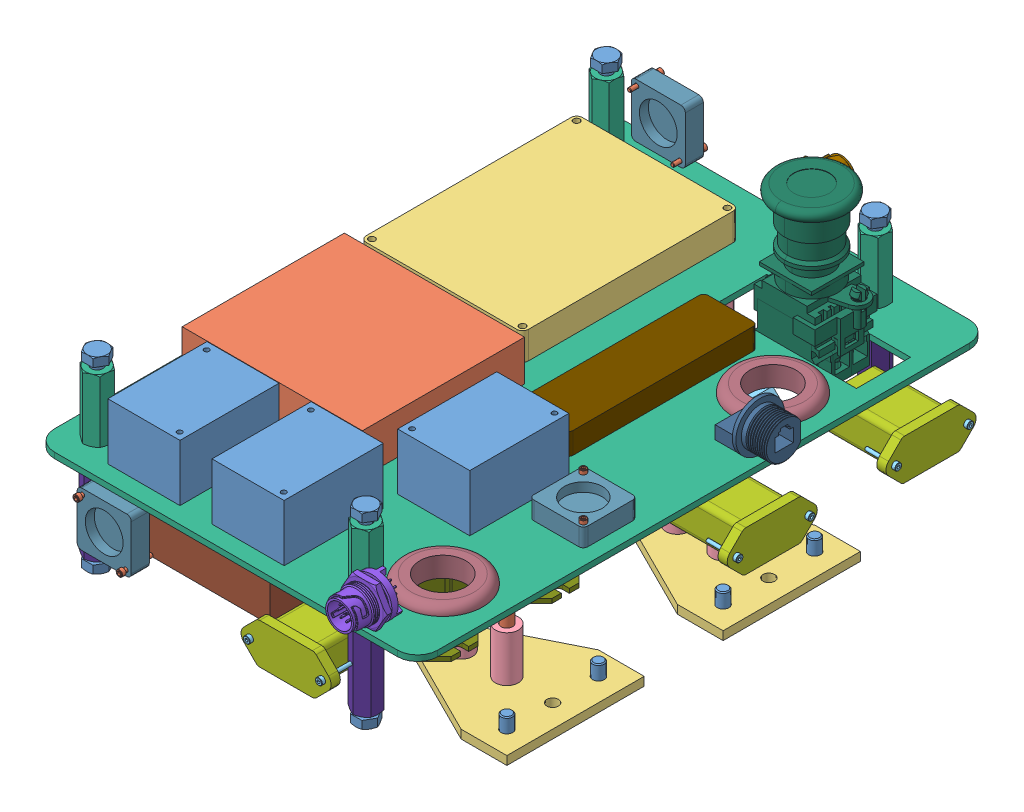
SolidWorks assembly ElectronicsCase2, configuration Default. Lengths in mm.
Overall size (226.41 163.38 353.07).
72 component instances, 27 part files, 172 mates.
Components (placement in the parent):
- Case-1: Case [Default] at (142.0655 -57.4073 111.1564) size (215.9 91.69 320.68) (hidden)
- EPOS$ EB Simple-1: EPOS$ EB Simple [Default] at (193.2592 221.0123 283.0081) x (1 0 0) z (0 0 -1) size (40 31.35 55)
- EPOS4 EB Micro-1: EPOS4 EB Micro [Default] at (252.5557 20.6679 36.3716) x (-1 0 0) z (0 0 1) size (100 22.5 90)
- LattePandaSimple-1: LattePandaSimple [Default] at (486.6352 212.549 -22.0114) x (0 0 -1) z (-1 0 0) size (120 15.18 90)
- EPOS$ EB Simple-2: EPOS$ EB Simple [Default] at (230.3992 -193.3265 -202.9705) size (40 31.35 55)
- EPOS$ EB Simple-3: EPOS$ EB Simple [Default] at (135.4792 221.0123 283.0081) x (1 0 0) z (0 0 -1) size (40 31.35 55)
- Cover^ElectronicsCase2-1: Cover^ElectronicsCase2 [Default] at (2.0429 34.2804 -33.3636) size (219.08 3.17 323.85) (hidden, virtual)
- Relay2-1: Relay2 [Default] at (225.8855 -55.8071 -151.3526) x (0 0 -1) z (0 1 0) size (45.49 58.42 35.56)
- Relay2-2: Relay2 [Default] at (167.4655 -55.8071 -151.3526) x (0 0 1) z (0 1 0) size (45.49 58.42 35.56)
- Terminal^ElectronicsCase2-1: Terminal^ElectronicsCase2 [Default] at (281.6155 -55.8071 -130.5286) x (1 0 0) z (0 0 -1) size (11.6 15.07 19.84) (virtual)
- Shelf^ElectronicsCase2-1: Shelf^ElectronicsCase2 [Default] at (0 -5.0071 0) size (212.7 3.17 317.47) (virtual)
- Part2^ElectronicsCase2-1: Part2^ElectronicsCase2 [Default] at origin (virtual)
- Power Plug ThroughHole^ElectronicsCase2-1: Power Plug ThroughHole^ElectronicsCase2 [Default] at (357.9655 -33.0571 -168.6436) x (0 0 1) z (-1 0 0) size (50 22.5 43.5) (virtual)
- Motor ThroughHole-1: Motor ThroughHole [Default] at (330.8405 16.2247 127.3562) x (0.866025 0.5 0) z (0 0 1) size (25.66 25.67 28.2)
- Electromagnet ThroughHole-1: Electromagnet ThroughHole [Default] at (256.4457 16.2247 -225.7184) x (-0.866025 0.5 0) z (0 0 -1) size (22.5 25.67 24.8)
- Power Plug ThroughHole^ElectronicsCase2-2: Power Plug ThroughHole^ElectronicsCase2 [Default] at (357.9655 -33.0571 -80.5436) x (0 0 1) z (-1 0 0) size (50 22.5 43.5) (virtual)
- Ethernet ThroughHole^ElectronicsCase2-1: Ethernet ThroughHole^ElectronicsCase2 [Default] at (356.3653 16.2247 -80.5436) x (0 0 1) z (-1 0 0) size (27 27 30.41) (virtual)
- Terminal^ElectronicsCase2-2: Terminal^ElectronicsCase2 [Default] at (281.6155 -55.8071 -150.3686) x (1 0 0) z (0 0 -1) size (11.6 15.07 19.84) (virtual)
- Power Supply^ElectronicsCase2-1: Power Supply^ElectronicsCase2 [Default] at (199.2155 -55.8071 1.8348) x (0 0 1) z (-1 0 0) size (154 40 88.9) (virtual)
- USB-C Adapter^ElectronicsCase2-1: USB-C Adapter^ElectronicsCase2 [Default] at (281.6155 -55.8071 -77.1111) x (0 0 -1) z (1 0 0) size (41.27 46.83 41.27) (virtual)
- Grommets3-1: Grommets3 [9600K217] at (325.8853 -2.6259 -118.1061) x (0.159498 0 0.987198) z (-0.987198 0 0.159498) size (44.45 11.11 44.45)
- Grommets3-2: Grommets3 [9600K217] at (325.8853 -2.6259 65.1062) x (-0.999275 0 0.038074) z (-0.038074 0 -0.999275) size (44.45 11.11 44.45)
- Power Plug ThroughHole^ElectronicsCase2-3: Power Plug ThroughHole^ElectronicsCase2 [Default] at (290.0905 -30.2823 111.1564) x (-1 0 0) z (0 0 -1) size (50 22.5 43.5) (virtual)
- Fan^ElectronicsCase2-1: Fan^ElectronicsCase2 [Default] at (182.4655 16.2247 -207.9184) size (30 30 10) (virtual)
- Fan^ElectronicsCase2-2: Fan^ElectronicsCase2 [Default] at (182.4655 -26.5323 99.5562) size (30 30 10) (virtual)
- Fan^ElectronicsCase2-3: Fan^ElectronicsCase2 [Default] at (333.3505 -1.8321 -5.4264) x (1 0 0) z (0 1 0) size (30 30 10) (virtual)
- Emergency Stop-1: Emergency Stop [Default] at (306.953 37.4554 -158.5061) x (0 0 1) z (0 1 0) size (40 46.39 86.7)
- Emergency Relay^ElectronicsCase2-1: Emergency Relay^ElectronicsCase2 [Default] at (277.6655 -55.8071 -17.1136) size (68 48.5 33) (virtual)
- Emergency Relay^ElectronicsCase2-2: Emergency Relay^ElectronicsCase2 [Default] at (277.6655 -55.8071 38.7464) size (68 48.5 33) (virtual)
- Standoff-1: Standoff [93505A200] at (310.3405 -24.0571 92.1064) x (0 1 0) z (-0.5 0 0.866025) size (64.39 14.66 12.7)
- Standoff-2: Standoff [93505A200] at (161.1155 -24.0571 92.1064) x (0 1 0) z (-0.5 0 0.866025) size (64.39 14.66 12.7)
- Standoff-3: Standoff [93505A200] at (161.1155 -24.0571 -190.4686) x (0 1 0) z (-1 0 0) size (64.39 14.66 12.7)
- Standoff-4: Standoff [93505A200] at (310.3405 -24.0571 -190.4686) x (0 1 0) z (-0.837138 0 0.546991) size (64.39 14.66 12.7)
- USB Hub^ElectronicsCase2-1: USB Hub^ElectronicsCase2 [Default] at (285.3217 -1.8321 -82.732) size (29.97 11.94 104.9) (virtual)
- hex bolt_ai-5: hex bolt_ai [HBOLT 0.2500-20x0.5x0.5-N] at (310.3405 -62.1825 92.1064) x (0 1 0) z (0 0 1) size (17.48 12.85 11.13)
- hex bolt_ai-6: hex bolt_ai [HBOLT 0.2500-20x0.5x0.5-N] at (161.1155 -62.1825 92.1064) x (0 1 0) z (0 0 1) size (17.48 12.85 11.13)
- hex bolt_ai-7: hex bolt_ai [HBOLT 0.2500-20x0.5x0.5-N] at (161.1155 -62.1825 -190.4686) x (0 1 0) z (0 0 1) size (17.48 12.85 11.13)
- hex bolt_ai-8: hex bolt_ai [HBOLT 0.2500-20x0.5x0.5-N] at (310.3405 -62.1825 -190.4686) x (0 1 0) z (0 0 1) size (17.48 12.85 11.13)
- socket head cap screw_ai-1: socket head cap screw_ai [HX-SHCS 0.086-56x0.625x0.625-N] at (170.4655 -14.5323 113.3408) x (0 0 -1) z (1 0 0) size (18.06 3.56 3.56)
- socket head cap screw_ai-2: socket head cap screw_ai [HX-SHCS 0.086-56x0.625x0.625-N] at (194.4655 -38.5323 113.3408) x (0 0 -1) z (1 0 0) size (18.06 3.56 3.56)
- socket head cap screw_ai-3: socket head cap screw_ai [HX-SHCS 0.086-56x0.625x0.625-N] at (170.4655 28.2247 -211.703) x (0 0 1) z (-1 0 0) size (18.06 3.56 3.56)
- socket head cap screw_ai-4: socket head cap screw_ai [HX-SHCS 0.086-56x0.625x0.625-N] at (194.4655 4.2247 -211.703) x (0 0 1) z (-1 0 0) size (18.06 3.56 3.56)
- socket head cap screw_ai-5: socket head cap screw_ai [HX-SHCS 0.086-56x0.625x0.625-N] at (321.3505 10.3523 -17.4264) x (0 -1 0) z (0 0 1) size (18.06 3.56 3.56)
- socket head cap screw_ai-7: socket head cap screw_ai [HX-SHCS 0.086-56x0.625x0.625-N] at (345.3505 10.3523 6.5736) x (0 -1 0) z (0 0 1) size (18.06 3.56 3.56)
- T-Framing-1: T-Framing [47065T278] at (345.2655 -85.1886 -71.0786) x (0 0 -1) z (0 1 0) size (76.2 76.2 4.76)
- T-Framing-2: T-Framing [47065T278] at (345.2655 -85.1886 48.9164) x (0 0 -1) z (0 1 0) size (76.2 76.2 4.76)
- hex bolt_ai-9: hex bolt_ai [HBOLT 0.2500-28x0.5x0.5-N] at (332.5655 -92.345 -134.5786) x (0 1 0) z (0 0 1) size (17.48 12.85 11.13)
- hex bolt_ai-10: hex bolt_ai [HBOLT 0.2500-28x0.5x0.5-N] at (332.5655 -92.345 -83.7786) x (0 1 0) z (0 0 1) size (17.48 12.85 11.13)
- hex bolt_ai-11: hex bolt_ai [HBOLT 0.2500-28x0.5x0.5-N] at (332.5655 -92.345 -14.5836) x (0 1 0) z (0 0 1) size (17.48 12.85 11.13)
- hex bolt_ai-12: hex bolt_ai [HBOLT 0.2500-28x0.5x0.5-N] at (332.5655 -92.345 36.2164) x (0 1 0) z (0 0 1) size (17.48 12.85 11.13)
- socket head cap screw_ai-8: socket head cap screw_ai [HX-SHCS 0.25-20x1.75x1.25-N] at (307.1655 -93.9198 -109.1786) x (0 1 0) z (0 0 1) size (50.8 9.53 9.53)
- socket head cap screw_ai-9: socket head cap screw_ai [HX-SHCS 0.25-20x1.75x1.25-N] at (281.7655 -93.9198 -109.1786) x (0 1 0) z (0 0 1) size (50.8 9.53 9.53)
- socket head cap screw_ai-10: socket head cap screw_ai [HX-SHCS 0.25-20x1.75x1.25-N] at (307.1655 -93.9198 10.8164) x (0 1 0) z (0 0 1) size (50.8 9.53 9.53)
- socket head cap screw_ai-11: socket head cap screw_ai [HX-SHCS 0.25-20x1.75x1.25-N] at (281.7655 -93.9198 10.8164) x (0 1 0) z (0 0 1) size (50.8 9.53 9.53)
- Spacers-1: Spacers [92510A769] at (307.1655 -70.1073 -109.1786) x (1 0 0) z (0 -1 0) size (12.7 12.7 25.4)
- Spacers-2: Spacers [92510A769] at (281.7655 -70.1073 -109.1786) x (1 0 0) z (0 -1 0) size (12.7 12.7 25.4)
- Spacers-3: Spacers [92510A769] at (281.7655 -70.1073 10.8164) x (1 0 0) z (0 -1 0) size (12.7 12.7 25.4)
- Spacers-4: Spacers [92510A769] at (307.1655 -70.1073 10.8164) x (1 0 0) z (0 -1 0) size (12.7 12.7 25.4)
- socket head cap screw_am-1: socket head cap screw_am [B18.3.1M - 2 x 0.4 x 16 Hex SHCS -- 16NHX] at (365.0655 -33.0571 -60.5436) x (-1 0 0) z (0 0.924225 0.381849) size (18 3.8 3.8)
- socket head cap screw_am-2: socket head cap screw_am [B18.3.1M - 2 x 0.4 x 16 Hex SHCS -- 16NHX] at (365.0655 -33.0571 -100.5436) x (-1 0 0) z (0 0.924225 0.381849) size (18 3.8 3.8)
- socket head cap screw_am-3: socket head cap screw_am [B18.3.1M - 2 x 0.4 x 16 Hex SHCS -- 16NHX] at (365.0655 -33.0571 -148.6436) x (-1 0 0) z (0 0.924225 0.381849) size (18 3.8 3.8)
- socket head cap screw_am-4: socket head cap screw_am [B18.3.1M - 2 x 0.4 x 16 Hex SHCS -- 16NHX] at (365.0655 -33.0571 -188.6436) x (-1 0 0) z (0 0.924225 0.381849) size (18 3.8 3.8)
- socket head cap screw_am-5: socket head cap screw_am [B18.3.1M - 2 x 0.4 x 16 Hex SHCS -- 16NHX] at (270.0905 -30.2823 118.2564) x (0 0 -1) z (1 0 0) size (18 3.8 3.8)
- socket head cap screw_am-6: socket head cap screw_am [B18.3.1M - 2 x 0.4 x 16 Hex SHCS -- 16NHX] at (310.0905 -30.2823 118.2564) x (0 0 -1) z (1 0 0) size (18 3.8 3.8)
- Standoff Top-1: Standoff Top [91780A666] at (310.3405 16.8191 92.1064) x (-0.401704 0 -0.915769) z (0 1 0) size (12.7 14.66 35.92)
- Standoff Top-2: Standoff Top [91780A666] at (310.3405 16.8191 -190.4686) x (-0.401704 0 -0.915769) z (0 1 0) size (12.7 14.66 35.92)
- Standoff Top-3: Standoff Top [91780A666] at (161.1155 16.8191 92.1064) x (-0.401704 0 -0.915769) z (0 1 0) size (12.7 14.66 35.92)
- Standoff Top-4: Standoff Top [91780A666] at (161.1155 16.8191 -190.4686) x (-0.401704 0 -0.915769) z (0 1 0) size (12.7 14.66 35.92)
- hex bolt_ai-13: hex bolt_ai [HBOLT 0.2500-20x0.5x0.5-N] at (310.3405 42.2306 -190.4686) x (0 -1 0) z (0 0 1) size (17.48 12.85 11.13)
- hex bolt_ai-14: hex bolt_ai [HBOLT 0.2500-20x0.5x0.5-N] at (161.1155 42.2306 -190.4686) x (0 -1 0) z (0 0 1) size (17.48 12.85 11.13)
- hex bolt_ai-15: hex bolt_ai [HBOLT 0.2500-20x0.5x0.5-N] at (161.1155 42.2306 92.1064) x (0 -1 0) z (0 0 1) size (17.48 12.85 11.13)
- hex bolt_ai-16: hex bolt_ai [HBOLT 0.2500-20x0.5x0.5-N] at (310.3405 42.2306 92.1064) x (0 -1 0) z (0 0 1) size (17.48 12.85 11.13)
Mates (geometry in assembly coordinates):
- Coincident3: coincident aligned: plane of EPOS$ EB Simple-2 through (299.0857 29.5179 21.8686) normal (0 1 0); plane of EPOS$ EB Simple-3 through (135.4792 29.5179 283.0081) normal (0 1 0)
- Coincident4: coincident aligned: plane of EPOS$ EB Simple-1 through (193.2592 29.5179 283.0081) normal (0 1 0); plane of EPOS$ EB Simple-3 through (135.4792 29.5179 283.0081) normal (0 1 0)
- Concentric1: concentric anti-aligned: cylinder of Case-1 through (345.2655 34.2816 -196.8186) axis (0 1 0) radius 12.7; cylinder of Cover^ElectronicsCase2-1 through (345.2655 35.8679 -196.8186) axis (0 -1 0) radius 14.2875
- Concentric2: concentric aligned: cylinder of Case-1 through (154.7655 34.2816 -196.8186) axis (0 -1 0) radius 12.7; cylinder of Cover^ElectronicsCase2-1 through (154.7655 35.8679 -196.8186) axis (0 -1 0) radius 14.2875
- Coincident37: coincident anti-aligned: plane of Case-1 through (142.0655 -55.8071 111.1564) normal (0 1 0); plane of Relay2-1 through (167.4655 -55.8071 -196.8186) normal (0 -1 0)
- Coincident38: coincident anti-aligned: plane of Case-1 through (142.0655 -55.8071 111.1564) normal (0 1 0); plane of Relay2-2 through (225.8855 -55.8071 -105.8866) normal (0 -1 0)
- Coincident67: coincident anti-aligned: plane of EPOS4 EB Micro-1 through (252.5557 -1.8321 36.3716) normal (0 -1 0); plane of Shelf^ElectronicsCase2-1 through (345.2655 -1.8321 98.4564) normal (0 1 0)
- Coincident68: coincident aligned: plane of EPOS4 EB Micro-1 through (252.5557 -1.8321 36.3716) normal (0 -1 0); plane of EPOS$ EB Simple-2 through (230.3992 -1.8321 -202.9705) normal (0 -1 0)
- Coincident69: coincident anti-aligned: plane of LattePandaSimple-1 through (233.9714 -1.8321 -102.8559) normal (0 -1 0); plane of Shelf^ElectronicsCase2-1 through (345.2655 -1.8321 98.4564) normal (0 1 0)
- Coincident72: coincident anti-aligned: plane of Case-1 through (356.3653 34.2816 111.1564) normal (-1 0 0); plane of Ethernet ThroughHole^ElectronicsCase2-1 through (356.3653 16.2247 -80.5436) normal (1 0 0)
- Coincident73: coincident aligned: plane of Power Plug ThroughHole^ElectronicsCase2-1 through (357.9655 -33.0571 -148.6436) normal (-1 0 0); plane of Power Plug ThroughHole^ElectronicsCase2-2 through (357.9655 -33.0571 -60.5436) normal (-1 0 0)
- Coincident74: coincident anti-aligned: plane of Case-1 through (357.9655 34.2816 111.1564) normal (1 0 0); plane of Power Plug ThroughHole^ElectronicsCase2-2 through (357.9655 -33.0571 -60.5436) normal (-1 0 0)
- Coincident75: coincident aligned: plane of Power Plug ThroughHole^ElectronicsCase2-1 through (363.0655 -21.8071 -154.0651) normal (0 1 0); plane of Power Plug ThroughHole^ElectronicsCase2-2 through (363.0655 -21.8071 -65.9651) normal (0 1 0)
- Perpendicular1: perpendicular: plane of Power Plug ThroughHole^ElectronicsCase2-2 through (363.0655 -21.8071 -65.9651) normal (0 1 0); plane of Ethernet ThroughHole^ElectronicsCase2-1 through (369.6653 10.9864 -89.6436) normal (0 0 -1)
- Parallel2: parallel aligned: plane of Case-1 through (142.0655 34.2816 111.1564) normal (0 1 0); plane of Power Plug ThroughHole^ElectronicsCase2-2 through (363.0655 -21.8071 -65.9651) normal (0 1 0)
- Coincident76: coincident anti-aligned: plane of Case-1 through (142.0655 -55.8071 111.1564) normal (0 1 0); plane of Terminal^ElectronicsCase2-1 through (281.6155 -55.8071 -130.5286) normal (0 -1 0)
- Coincident78: coincident aligned: plane of Terminal^ElectronicsCase2-1 through (281.6155 -40.7371 -130.5286) normal (0 1 0); plane of Terminal^ElectronicsCase2-2 through (281.6155 -40.7371 -150.3686) normal (0 1 0)
- Concentric10: concentric anti-aligned: cylinder of Case-1 through (154.7655 34.2816 98.4564) axis (0 1 0) radius 12.7; cylinder of Shelf^ElectronicsCase2-1 through (154.7655 -1.8321 98.4564) axis (0 -1 0) radius 11.0998
- Concentric11: concentric aligned: cylinder of Case-1 through (345.2655 34.2816 98.4564) axis (0 -1 0) radius 11.0998; cylinder of Shelf^ElectronicsCase2-1 through (345.2655 -1.8321 98.4564) axis (0 -1 0) radius 11.0998
- Distance4: distance = 12.7 mm anti-aligned: plane of Power Plug ThroughHole^ElectronicsCase2-1 through (319.5655 -43.1071 -157.7436) normal (0 -1 0); plane of Case-1 through (142.0655 -55.8071 111.1564) normal (0 1 0)
- Coincident83: coincident anti-aligned: plane of Case-1 through (142.0655 -55.8071 111.1564) normal (0 1 0); plane of Power Supply^ElectronicsCase2-1 through (199.2155 -55.8071 1.8348) normal (0 -1 0)
- Parallel3: parallel anti-aligned: plane of Case-1 through (356.3653 34.2816 111.1564) normal (-1 0 0); plane of Power Supply^ElectronicsCase2-1 through (243.6655 -15.8071 78.8348) normal (1 0 0)
- Distance6: distance = 6.35 mm anti-aligned: plane of EPOS$ EB Simple-1 through (193.2592 29.5179 283.0081) normal (0 1 0); plane of Cover^ElectronicsCase2-1 through (154.7655 35.8679 -196.8186) normal (0 -1 0)
- Coincident94: coincident anti-aligned: plane of Case-1 through (142.0655 -55.8071 111.1564) normal (0 1 0); plane of USB-C Adapter^ElectronicsCase2-1 through (281.6155 -55.8071 -77.1111) normal (0 -1 0)
- Distance11: distance = 8.89 mm anti-aligned: plane of LattePandaSimple-1 through (185.3257 -151.8321 -62.5184) normal (0 0 1); plane of EPOS4 EB Micro-1 through (252.5557 -1.8321 -53.6284) normal (0 0 -1)
- Coincident103: coincident: line of Case-1 through (154.7655 -57.4073 98.4564) axis (0 0 -1); plane of Power Supply^ElectronicsCase2-1 through (154.7655 -15.8071 78.8348) normal (-1 0 0)
- Distance14: distance = 8.89 mm anti-aligned: plane of LattePandaSimple-1 through (152.5557 -151.8321 -104.2384) normal (-1 0 0); plane of Case-1 through (143.6657 34.2816 111.1564) normal (1 0 0)
- Distance17: distance = 17.78 mm anti-aligned: plane of EPOS$ EB Simple-3 through (215.4157 -69.8395 73.0639) normal (1 0 0); plane of EPOS$ EB Simple-1 through (233.1957 -69.8395 73.0639) normal (-1 0 0)
- Coincident105: coincident aligned: plane of EPOS$ EB Simple-1 through (253.0957 -69.8395 100.4639) normal (0 0 1); plane of EPOS$ EB Simple-3 through (195.3157 -69.8395 100.4639) normal (0 0 1)
- Distance18: distance = 17.78 mm anti-aligned: plane of EPOS4 EB Micro-1 through (252.5557 -1.8321 36.3716) normal (1 0 0); plane of EPOS$ EB Simple-2 through (270.3357 97.5252 6.9736) normal (-1 0 0)
- Coincident110: coincident aligned: plane of Grommets3-2 through (325.4018 2.9304 52.4155) normal (0 1 0); plane of Grommets3-1 through (313.3479 2.9304 -116.0804) normal (0 1 0)
- Coincident111: coincident anti-aligned: plane of Shelf^ElectronicsCase2-1 through (345.2655 -1.8321 98.4564) normal (0 1 0); plane of Grommets3-2 through (325.2204 -1.8321 47.6564) normal (0 -1 0)
- Distance19: distance = 17.78 mm: cylinder of Grommets3-2 through (325.8853 -8.1821 65.1062) axis (0 -1 0) radius 12.7; plane of Case-1 through (356.3653 34.2816 111.1564) normal (-1 0 0)
- Distance23: distance = 3.175 mm: line of Case-1 through (357.9655 -44.7073 -196.8186) axis (0 1 0); cylinder of Power Plug ThroughHole^ElectronicsCase2-1 through (363.0655 -33.0571 -188.6436) axis (-1 0 0) radius 5
- Width3: width aligned: plane of Shelf^ElectronicsCase2-1 through (345.2655 -1.8321 98.4564) normal (0 1 0); plane of Motor ThroughHole-1 through (142.0655 34.2816 111.1564) normal (0 1 0); plane of Case-1 through (330.8405 27.3372 112.6439) normal (0 1 0); plane of Motor ThroughHole-1 through (330.8405 5.1122 112.6439) normal (0 -1 0)
- Width4: width: plane of Shelf^ElectronicsCase2-1 through (345.2655 -1.8321 98.4564) normal (0 1 0); plane of Ethernet ThroughHole^ElectronicsCase2-1 through (142.0655 34.2816 111.1564) normal (0 1 0); cylinder of Case-1 through (354.3653 16.2247 -80.5436) axis (1 0 0) radius 13.5
- Coincident115: coincident anti-aligned: plane of Case-1 through (142.0655 34.2816 109.5562) normal (0 0 -1); plane of Motor ThroughHole-1 through (330.8405 16.2247 109.5562) normal (0 0 1)
- Distance35: distance = 50.8 mm aligned: plane of Power Supply^ElectronicsCase2-1 through (199.2155 -55.8071 1.8348) normal (0 -1 0); plane of Shelf^ElectronicsCase2-1 through (345.2655 -5.0071 98.4564) normal (0 -1 0)
- Distance36: distance = 3.175 mm: plane of Power Plug ThroughHole^ElectronicsCase2-3 through (275.5121 -41.5323 116.2564) normal (0 -1 0); line of Case-1 through (154.7655 -44.7073 111.1564) axis (1 0 0)
- Distance37: distance = 3.175 mm: cylinder of Motor ThroughHole-1 through (330.8405 16.2247 109.6962) axis (0 0 -1) radius 11.25; line of Case-1 through (345.2655 -44.7073 111.1564) axis (0 1 0)
- Width5: width aligned: plane of Shelf^ElectronicsCase2-1 through (345.2655 -1.8321 98.4564) normal (0 1 0); plane of Electromagnet ThroughHole-1 through (142.0655 34.2816 111.1564) normal (0 1 0); plane of Case-1 through (250.0299 27.3372 -209.4184) normal (0 1 0); plane of Electromagnet ThroughHole-1 through (262.8615 5.1122 -209.4184) normal (0 -1 0)
- Coincident118: coincident anti-aligned: plane of Case-1 through (142.0655 34.2816 -207.9184) normal (0 0 1); plane of Electromagnet ThroughHole-1 through (256.4457 16.2247 -207.9184) normal (0 0 -1)
- Coincident119: coincident anti-aligned: plane of Case-1 through (142.0655 34.2816 111.1564) normal (0 0 1); plane of Power Plug ThroughHole^ElectronicsCase2-3 through (270.0905 -30.2823 111.1564) normal (0 0 -1)
- Coincident120: coincident anti-aligned: plane of Case-1 through (142.0655 34.2816 -207.9184) normal (0 0 1); plane of Fan^ElectronicsCase2-1 through (182.4655 16.2247 -207.9184) normal (0 0 -1)
- Coincident121: coincident anti-aligned: plane of Case-1 through (142.0655 34.2816 109.5562) normal (0 0 -1); plane of Fan^ElectronicsCase2-2 through (182.4655 -26.5323 109.5562) normal (0 0 1)
- Coincident122: coincident aligned: plane of Power Plug ThroughHole^ElectronicsCase2-3 through (275.5121 -41.5323 116.2564) normal (0 -1 0); plane of Fan^ElectronicsCase2-2 through (197.4655 -41.5323 109.5562) normal (0 -1 0)
- Width7: width aligned: plane of Fan^ElectronicsCase2-1 through (197.4655 31.2247 -197.9184) normal (0 1 0); plane of Electromagnet ThroughHole-1 through (197.4655 1.2247 -197.9184) normal (0 -1 0); plane of Fan^ElectronicsCase2-1 through (250.0299 27.3372 -209.4184) normal (0 1 0); plane of Electromagnet ThroughHole-1 through (262.8615 5.1122 -209.4184) normal (0 -1 0)
- Coincident125: coincident anti-aligned: plane of Shelf^ElectronicsCase2-1 through (345.2655 -1.8321 98.4564) normal (0 1 0); plane of Fan^ElectronicsCase2-3 through (333.3505 -1.8321 -5.4264) normal (0 -1 0)
- Width8: width aligned: plane of Case-1 through (142.0655 34.2816 109.5562) normal (0 0 -1); plane of EPOS$ EB Simple-3 through (252.5557 -1.8321 36.3716) normal (0 0 1); plane of EPOS4 EB Micro-1 through (195.3157 -69.8395 45.4639) normal (0 0 -1); plane of EPOS$ EB Simple-3 through (195.3157 -69.8395 100.4639) normal (0 0 1)
- Coincident128: coincident aligned: plane of Power Supply^ElectronicsCase2-1 through (199.2155 -55.8071 1.8348) normal (0 -1 0); plane of Emergency Relay^ElectronicsCase2-1 through (277.6655 -55.8071 -17.1136) normal (0 -1 0)
- Coincident129: coincident aligned: plane of Emergency Relay^ElectronicsCase2-1 through (277.6655 -55.8071 -17.1136) normal (0 -1 0); plane of Emergency Relay^ElectronicsCase2-2 through (277.6655 -55.8071 38.7464) normal (0 -1 0)
- Coincident138: coincident anti-aligned: plane of Terminal^ElectronicsCase2-1 through (287.4155 -40.7371 -140.4486) normal (0 0 -1); plane of Terminal^ElectronicsCase2-2 through (287.4155 -40.7371 -140.4486) normal (0 0 1)
- Coincident139: coincident aligned: plane of Terminal^ElectronicsCase2-1 through (287.4155 -40.7371 -120.6086) normal (1 0 0); plane of Terminal^ElectronicsCase2-2 through (287.4155 -40.7371 -140.4486) normal (1 0 0)
- Distance46: distance = 31.75 mm: cylinder of Grommets3-2 through (325.8853 -8.1821 65.1062) axis (0 -1 0) radius 12.7; plane of Case-1 through (142.0655 34.2816 109.5562) normal (0 0 -1)
- Coincident142: coincident aligned: plane of Standoff-3 through (161.1155 -5.0071 -197.8009) normal (0 1 0); plane of Standoff-4 through (306.3298 -5.0071 -196.6067) normal (0 1 0)
- Coincident143: coincident aligned: plane of Standoff-2 through (154.7655 -5.0071 88.4403) normal (0 1 0); plane of Standoff-4 through (306.3298 -5.0071 -196.6067) normal (0 1 0)
- Coincident144: coincident aligned: plane of Standoff-1 through (303.9905 -5.0071 88.4403) normal (0 1 0); plane of Standoff-2 through (154.7655 -5.0071 88.4403) normal (0 1 0)
- Concentric13: concentric anti-aligned: cylinder of Shelf^ElectronicsCase2-1 through (310.3405 -5.0081 -190.4686) axis (0 1 0) radius 3.175; cylinder of Standoff-4 through (310.3405 -24.0571 -190.4686) axis (0 -1 0) radius 2.3476
- Concentric14: concentric anti-aligned: cylinder of Shelf^ElectronicsCase2-1 through (161.1155 -5.0081 -190.4686) axis (0 1 0) radius 3.175; cylinder of Standoff-3 through (161.1155 -24.0571 -190.4686) axis (0 -1 0) radius 2.3476
- Coincident146: coincident aligned: plane of EPOS4 EB Micro-1 through (152.5557 -1.8321 36.3716) normal (-1 0 0); plane of LattePandaSimple-1 through (152.5557 -151.8321 -104.2384) normal (-1 0 0)
- Distance47: distance = 25.4 mm anti-aligned: plane of LattePandaSimple-1 through (185.3257 -151.8321 -182.5184) normal (0 0 -1); plane of Case-1 through (142.0655 34.2816 -207.9184) normal (0 0 1)
- Distance48: distance = 31.75 mm anti-aligned: plane of EPOS$ EB Simple-3 through (175.4157 -69.8395 73.0639) normal (-1 0 0); plane of Case-1 through (143.6657 34.2816 111.1564) normal (1 0 0)
- Concentric15: concentric anti-aligned: cylinder of Shelf^ElectronicsCase2-1 through (161.1155 -5.0081 92.1064) axis (0 1 0) radius 3.175; cylinder of Standoff-2 through (161.1155 -24.0571 92.1064) axis (0 -1 0) radius 2.3476
- Concentric16: concentric anti-aligned: cylinder of Shelf^ElectronicsCase2-1 through (310.3405 -5.0081 92.1064) axis (0 1 0) radius 3.175; cylinder of Standoff-1 through (310.3405 -24.0571 92.1064) axis (0 -1 0) radius 2.3476
- Width17: width anti-aligned: plane of Power Plug ThroughHole^ElectronicsCase2-2 through (319.5655 -26.0071 -91.4436) normal (-1 0 0); plane of Power Supply^ElectronicsCase2-1 through (243.6655 -15.8071 78.8348) normal (1 0 0); plane of Terminal^ElectronicsCase2-1 through (287.4155 -40.7371 -120.6086) normal (1 0 0); plane of Terminal^ElectronicsCase2-1 through (275.8155 -40.7371 -120.6086) normal (-1 0 0)
- Distance53: distance = 38.1 mm aligned: plane of Emergency Stop-1 through (321.453 29.8554 -173.0061) normal (0 0 -1); plane of Cover^ElectronicsCase2-1 through (154.7655 35.8679 -211.1061) normal (0 0 -1)
- Distance54: distance = 38.1 mm aligned: plane of Emergency Stop-1 through (321.453 29.8554 -173.0061) normal (1 0 0); plane of Cover^ElectronicsCase2-1 through (359.553 35.8679 98.4564) normal (1 0 0)
- Distance55: distance = 12.7 mm: plane of Fan^ElectronicsCase2-1 through (167.4655 1.2247 -197.9184) normal (-1 0 0); line of Case-1 through (154.7655 -44.7073 -209.5186) axis (0 1 0)
- Distance56: distance = 38.1 mm: cylinder of Power Plug ThroughHole^ElectronicsCase2-2 through (363.0655 -33.0571 -100.5436) axis (-1 0 0) radius 5; cylinder of Power Plug ThroughHole^ElectronicsCase2-1 through (363.0655 -33.0571 -148.6436) axis (-1 0 0) radius 5
- Parallel10: parallel anti-aligned: plane of EPOS$ EB Simple-2 through (290.2357 97.5252 -20.4264) normal (0 0 -1); plane of Fan^ElectronicsCase2-3 through (348.3505 8.1679 9.5736) normal (0 0 1)
- Coincident164: coincident aligned: plane of EPOS$ EB Simple-2 through (290.2357 97.5252 -20.4264) normal (0 0 -1); plane of Fan^ElectronicsCase2-3 through (348.3505 8.1679 -20.4264) normal (0 0 -1)
- Width25: width anti-aligned: plane of EPOS$ EB Simple-2 through (310.3357 97.5252 6.9736) normal (1 0 0); plane of Case-1 through (356.3653 34.2816 111.1564) normal (-1 0 0); plane of Fan^ElectronicsCase2-3 through (318.3505 8.1679 9.5736) normal (-1 0 0); plane of Fan^ElectronicsCase2-3 through (348.3505 8.1679 9.5736) normal (1 0 0)
- Distance57: distance = 17.78 mm: cylinder of Grommets3-1 through (325.8853 -8.1821 -118.1061) axis (0 -1 0) radius 12.7; plane of Case-1 through (356.3653 34.2816 111.1564) normal (-1 0 0)
- Distance58: distance = 12.7 mm: plane of Shelf^ElectronicsCase2-1 through (346.813 -5.0081 -143.5061) normal (0 0 -1); cylinder of Grommets3-1 through (325.8853 -8.1821 -118.1061) axis (0 -1 0) radius 12.7
- Concentric22: concentric aligned: cylinder of Case-1 through (310.3405 34.2826 92.1064) axis (0 -1 0) radius 3.175; cylinder of hex bolt_ai-5 through (310.3405 -62.1825 92.1064) axis (0 -1 0) radius 3.175
- Coincident165: coincident anti-aligned: plane of Case-1 through (142.0655 -57.4073 111.1564) normal (0 -1 0); plane of hex bolt_ai-5 through (303.9174 -57.4073 92.1064) normal (0 1 0)
- Concentric23: concentric aligned: cylinder of Case-1 through (161.1155 34.2826 92.1064) axis (0 -1 0) radius 3.175; cylinder of hex bolt_ai-6 through (161.1155 -62.1825 92.1064) axis (0 -1 0) radius 3.175
- Coincident166: coincident anti-aligned: plane of Case-1 through (142.0655 -57.4073 111.1564) normal (0 -1 0); plane of hex bolt_ai-6 through (154.6924 -57.4073 92.1064) normal (0 1 0)
- Concentric24: concentric aligned: cylinder of Case-1 through (161.1155 34.2826 -190.4686) axis (0 -1 0) radius 3.175; cylinder of hex bolt_ai-7 through (161.1155 -62.1825 -190.4686) axis (0 -1 0) radius 3.175
- Coincident167: coincident anti-aligned: plane of Case-1 through (142.0655 -57.4073 111.1564) normal (0 -1 0); plane of hex bolt_ai-7 through (154.6924 -57.4073 -190.4686) normal (0 1 0)
- Concentric25: concentric aligned: cylinder of Case-1 through (310.3405 34.2826 -190.4686) axis (0 -1 0) radius 3.175; cylinder of hex bolt_ai-8 through (310.3405 -62.1825 -190.4686) axis (0 -1 0) radius 3.175
- Coincident168: coincident anti-aligned: plane of Case-1 through (142.0655 -57.4073 111.1564) normal (0 -1 0); plane of hex bolt_ai-8 through (303.9174 -57.4073 -190.4686) normal (0 1 0)
- Concentric26: concentric aligned: cylinder of Case-1 through (170.4655 -14.5323 -209.5196) axis (0 0 1) radius 1.2; cylinder of socket head cap screw_ai-1 through (170.4655 -14.5323 145.0908) axis (0 0 1) radius 1.778
- Coincident169: coincident anti-aligned: plane of Case-1 through (142.0655 34.2816 111.1564) normal (0 0 1); plane of socket head cap screw_ai-1 through (170.4655 -12.7543 111.1564) normal (0 0 -1)
- Concentric27: concentric aligned: cylinder of Case-1 through (194.4655 -38.5323 -209.5196) axis (0 0 1) radius 1.2; cylinder of socket head cap screw_ai-2 through (194.4655 -38.5323 145.0908) axis (0 0 1) radius 1.778
- Coincident170: coincident anti-aligned: plane of Case-1 through (142.0655 34.2816 111.1564) normal (0 0 1); plane of socket head cap screw_ai-2 through (194.4655 -36.7543 111.1564) normal (0 0 -1)
- Concentric28: concentric aligned: cylinder of Case-1 through (170.4655 28.2247 111.1574) axis (0 0 -1) radius 1.2; cylinder of socket head cap screw_ai-3 through (170.4655 28.2247 -243.453) axis (0 0 -1) radius 1.778
- Coincident171: coincident anti-aligned: plane of Case-1 through (142.0655 34.2816 -209.5186) normal (0 0 -1); plane of socket head cap screw_ai-3 through (170.4655 30.0027 -209.5186) normal (0 0 1)
- Concentric29: concentric aligned: cylinder of Case-1 through (194.4655 4.2247 111.1574) axis (0 0 -1) radius 1.2; cylinder of socket head cap screw_ai-4 through (194.4655 4.2247 -243.453) axis (0 0 -1) radius 1.778
- Coincident172: coincident anti-aligned: plane of Case-1 through (142.0655 34.2816 -209.5186) normal (0 0 -1); plane of socket head cap screw_ai-4 through (194.4655 6.0027 -209.5186) normal (0 0 1)
- Concentric30: concentric anti-aligned: cylinder of Fan^ElectronicsCase2-3 through (321.3505 8.1679 -17.4264) axis (0 -1 0) radius 1.2; cylinder of socket head cap screw_ai-5 through (321.3505 42.1023 -17.4264) axis (0 1 0) radius 1.0922
- Concentric31: concentric anti-aligned: cylinder of Fan^ElectronicsCase2-3 through (345.3505 8.1679 6.5736) axis (0 -1 0) radius 1.2; cylinder of socket head cap screw_ai-7 through (345.3505 42.1023 6.5736) axis (0 1 0) radius 1.0922
- Coincident173: coincident aligned: plane of Fan^ElectronicsCase2-3 through (333.3505 8.1679 -5.4264) normal (0 1 0); circle of socket head cap screw_ai-7
- Coincident174: coincident aligned: plane of Fan^ElectronicsCase2-3 through (333.3505 8.1679 -5.4264) normal (0 1 0); circle of socket head cap screw_ai-5
- Coincident175: coincident anti-aligned: plane of Shelf^ElectronicsCase2-1 through (345.2655 -1.8321 98.4564) normal (0 1 0); plane of USB Hub^ElectronicsCase2-1 through (285.3217 -1.8321 -82.732) normal (0 -1 0)
- Coincident176: coincident aligned: plane of EPOS$ EB Simple-2 through (270.3357 97.5252 6.9736) normal (-1 0 0); plane of USB Hub^ElectronicsCase2-1 through (270.3357 10.1059 -135.183) normal (-1 0 0)
- Width26: width: plane of Power Plug ThroughHole^ElectronicsCase2-2 through (319.5655 -40.1071 -94.4436) normal (0 0 -1); plane of Ethernet ThroughHole^ElectronicsCase2-1 through (319.5655 -40.1071 -66.6436) normal (0 0 1); cylinder of Power Plug ThroughHole^ElectronicsCase2-2 through (354.3653 16.2247 -80.5436) axis (1 0 0) radius 13.5
- Width30: width aligned: plane of USB Hub^ElectronicsCase2-1 through (270.3357 10.1059 -135.183) normal (-1 0 0); plane of Electromagnet ThroughHole-1 through (242.5557 -151.8321 -104.2384) normal (1 0 0); plane of LattePandaSimple-1 through (257.4457 21.7754 -200.9184) normal (0.999848 0 0.017452); plane of Electromagnet ThroughHole-1 through (255.4457 27.9885 -200.9184) normal (-0.999848 0 0.017452)
- Distance59: distance = 25.4 mm anti-aligned: plane of T-Framing-1 through (345.2655 -82.8073 -71.0786) normal (0 1 0); plane of Case-1 through (142.0655 -57.4073 111.1564) normal (0 -1 0)
- Coincident178: coincident aligned: plane of T-Framing-1 through (345.2655 -87.5698 -71.0786) normal (0 -1 0); plane of T-Framing-2 through (345.2655 -87.5698 48.9164) normal (0 -1 0)
- Coincident180: coincident aligned: plane of T-Framing-1 through (345.2655 -82.8073 -147.2786) normal (1 0 0); plane of T-Framing-2 through (345.2655 -82.8073 -27.2836) normal (1 0 0)
- Width33: width aligned: plane of Case-1 through (142.0655 34.2816 -209.5186) normal (0 0 -1); plane of Case-1 through (142.0655 34.2816 111.1564) normal (0 0 1); plane of T-Framing-2 through (319.8655 -82.8073 -27.2836) normal (0 0 -1); plane of T-Framing-1 through (345.2655 -82.8073 -71.0786) normal (0 0 1)
- Concentric33: concentric aligned: cylinder of T-Framing-1 through (332.5655 -82.8073 -134.5786) axis (0 -1 0) radius 3.2639; cylinder of hex bolt_ai-9 through (332.5655 -92.345 -134.5786) axis (0 -1 0) radius 3.175
- Coincident181: coincident anti-aligned: plane of T-Framing-1 through (345.2655 -87.5698 -71.0786) normal (0 -1 0); plane of hex bolt_ai-9 through (326.1424 -87.5698 -134.5786) normal (0 1 0)
- Concentric34: concentric aligned: cylinder of T-Framing-1 through (332.5655 -82.8073 -83.7786) axis (0 -1 0) radius 3.2639; cylinder of hex bolt_ai-10 through (332.5655 -92.345 -83.7786) axis (0 -1 0) radius 3.175
- Coincident182: coincident anti-aligned: plane of T-Framing-1 through (345.2655 -87.5698 -71.0786) normal (0 -1 0); plane of hex bolt_ai-10 through (326.1424 -87.5698 -83.7786) normal (0 1 0)
- Concentric35: concentric aligned: cylinder of T-Framing-2 through (332.5655 -82.8073 -14.5836) axis (0 -1 0) radius 3.2639; cylinder of hex bolt_ai-11 through (332.5655 -92.345 -14.5836) axis (0 -1 0) radius 3.175
- Coincident183: coincident anti-aligned: plane of T-Framing-2 through (345.2655 -87.5698 48.9164) normal (0 -1 0); plane of hex bolt_ai-11 through (326.1424 -87.5698 -14.5836) normal (0 1 0)
- Concentric36: concentric aligned: cylinder of T-Framing-2 through (332.5655 -82.8073 36.2164) axis (0 -1 0) radius 3.2639; cylinder of hex bolt_ai-12 through (332.5655 -92.345 36.2164) axis (0 -1 0) radius 3.175
- Coincident184: coincident anti-aligned: plane of T-Framing-2 through (345.2655 -87.5698 48.9164) normal (0 -1 0); plane of hex bolt_ai-12 through (326.1424 -87.5698 36.2164) normal (0 1 0)
- Concentric37: concentric aligned: cylinder of T-Framing-1 through (307.1655 -82.8073 -109.1786) axis (0 -1 0) radius 3.2639; cylinder of socket head cap screw_ai-8 through (307.1655 -125.6698 -109.1786) axis (0 -1 0) radius 4.7625
- Coincident185: coincident anti-aligned: plane of T-Framing-1 through (345.2655 -87.5698 -71.0786) normal (0 -1 0); plane of socket head cap screw_ai-8 through (302.403 -87.5698 -109.1786) normal (0 1 0)
- Concentric38: concentric aligned: cylinder of T-Framing-1 through (281.7655 -82.8073 -109.1786) axis (0 -1 0) radius 3.2639; cylinder of socket head cap screw_ai-9 through (281.7655 -125.6698 -109.1786) axis (0 -1 0) radius 4.7625
- Coincident186: coincident anti-aligned: plane of T-Framing-1 through (345.2655 -87.5698 -71.0786) normal (0 -1 0); plane of socket head cap screw_ai-9 through (277.003 -87.5698 -109.1786) normal (0 1 0)
- Concentric39: concentric aligned: cylinder of T-Framing-2 through (307.1655 -82.8073 10.8164) axis (0 -1 0) radius 3.2639; cylinder of socket head cap screw_ai-10 through (307.1655 -125.6698 10.8164) axis (0 -1 0) radius 4.7625
- Coincident187: coincident anti-aligned: plane of T-Framing-2 through (345.2655 -87.5698 48.9164) normal (0 -1 0); plane of socket head cap screw_ai-10 through (302.403 -87.5698 10.8164) normal (0 1 0)
- Concentric40: concentric aligned: cylinder of T-Framing-2 through (281.7655 -82.8073 10.8164) axis (0 -1 0) radius 3.2639; cylinder of socket head cap screw_ai-11 through (281.7655 -125.6698 10.8164) axis (0 -1 0) radius 4.7625
- Coincident188: coincident anti-aligned: plane of T-Framing-2 through (345.2655 -87.5698 48.9164) normal (0 -1 0); plane of socket head cap screw_ai-11 through (277.003 -87.5698 10.8164) normal (0 1 0)
- Coincident189: coincident aligned: plane of Spacers-1 through (307.1655 -57.4073 -109.1786) normal (0 1 0); plane of Spacers-2 through (281.7655 -57.4073 -109.1786) normal (0 1 0)
- Coincident190: coincident aligned: plane of Spacers-1 through (307.1655 -57.4073 -109.1786) normal (0 1 0); plane of Spacers-3 through (281.7655 -57.4073 10.8164) normal (0 1 0)
- Coincident191: coincident aligned: plane of Spacers-3 through (281.7655 -57.4073 10.8164) normal (0 1 0); plane of Spacers-4 through (307.1655 -57.4073 10.8164) normal (0 1 0)
- Coincident192: coincident anti-aligned: plane of Case-1 through (142.0655 -57.4073 111.1564) normal (0 -1 0); plane of Spacers-4 through (307.1655 -57.4073 10.8164) normal (0 1 0)
- Concentric41: concentric anti-aligned: cylinder of socket head cap screw_ai-10 through (307.1655 -125.6698 10.8164) axis (0 -1 0) radius 3.175; cylinder of Spacers-4 through (307.1655 -82.8073 10.8164) axis (0 1 0) radius 6.35
- Concentric42: concentric anti-aligned: cylinder of socket head cap screw_ai-11 through (281.7655 -125.6698 10.8164) axis (0 -1 0) radius 3.175; cylinder of Spacers-3 through (281.7655 -82.8073 10.8164) axis (0 1 0) radius 6.35
- Concentric43: concentric anti-aligned: cylinder of socket head cap screw_ai-8 through (307.1655 -125.6698 -109.1786) axis (0 -1 0) radius 3.175; cylinder of Spacers-1 through (307.1655 -82.8073 -109.1786) axis (0 1 0) radius 6.35
- Concentric44: concentric anti-aligned: cylinder of socket head cap screw_ai-9 through (281.7655 -125.6698 -109.1786) axis (0 -1 0) radius 3.175; cylinder of Spacers-2 through (281.7655 -82.8073 -109.1786) axis (0 1 0) radius 6.35
- Distance61: distance = 12.7 mm: line of Case-1 through (332.5655 -57.4073 -187.2891) axis (0 0 1); plane of T-Framing-2 through (345.2655 -82.8073 -27.2836) normal (1 0 0)
- Parallel14: parallel anti-aligned: plane of Case-1 through (142.0655 34.2816 -207.9184) normal (0 0 1); plane of Relay2-1 through (196.6755 -231.21 -196.8186) normal (0 0 -1)
- Coincident195: coincident anti-aligned: plane of Relay2-1 through (196.6755 -231.21 -151.3526) normal (0 0 1); plane of Relay2-2 through (196.6755 -231.21 -151.3526) normal (0 0 -1)
- Coincident196: coincident aligned: plane of Relay2-1 through (167.4655 -22.2791 -196.8186) normal (-1 0 0); plane of Relay2-2 through (167.4655 -22.2791 -105.8866) normal (-1 0 0)
- Coincident197: coincident: line of Case-1 through (154.7655 -57.4073 -196.8186) axis (1 0 0); plane of Relay2-1 through (196.6755 -231.21 -196.8186) normal (0 0 -1)
- Coincident198: coincident anti-aligned: plane of Power Supply^ElectronicsCase2-1 through (243.6655 -15.8071 78.8348) normal (1 0 0); plane of Emergency Relay^ElectronicsCase2-2 through (243.6655 -53.4071 38.7464) normal (-1 0 0)
- Coincident199: coincident aligned: plane of Emergency Relay^ElectronicsCase2-1 through (302.6655 -7.3071 -17.1136) normal (1 0 0); plane of Emergency Relay^ElectronicsCase2-2 through (302.6655 -7.3071 38.7464) normal (1 0 0)
- Distance63: distance = 22.86 mm anti-aligned: plane of Emergency Relay^ElectronicsCase2-2 through (277.6655 -7.3071 22.2464) normal (0 0 -1); plane of Emergency Relay^ElectronicsCase2-1 through (277.6655 -7.3071 -0.6136) normal (0 0 1)
- Width38: width: plane of Emergency Relay^ElectronicsCase2-1 through (277.6655 -7.3071 -0.6136) normal (0 0 1); plane of Emergency Relay^ElectronicsCase2-2 through (277.6655 -7.3071 22.2464) normal (0 0 -1); cylinder of Spacers-4 through (307.1655 -82.8073 10.8164) axis (0 1 0) radius 6.35
- Width39: width: plane of USB-C Adapter^ElectronicsCase2-1 through (302.253 -28.0259 -97.7486) normal (0 0 -1); plane of Terminal^ElectronicsCase2-1 through (287.4155 -40.7371 -120.6086) normal (0 0 1); cylinder of Spacers-2 through (281.7655 -82.8073 -109.1786) axis (0 1 0) radius 6.35
- Coincident200: coincident anti-aligned: plane of Relay2-1 through (167.4655 -22.2791 -196.8186) normal (-1 0 0); plane of Standoff-3 through (167.4655 -55.8071 -186.8024) normal (1 0 0)
- Width40: width aligned: plane of Power Supply^ElectronicsCase2-1 through (243.6655 -15.8071 78.8348) normal (1 0 0); plane of Power Plug ThroughHole^ElectronicsCase2-2 through (319.5655 -26.0071 -91.4436) normal (-1 0 0); plane of USB-C Adapter^ElectronicsCase2-1 through (302.253 -28.0259 -56.4736) normal (1 0 0); plane of USB-C Adapter^ElectronicsCase2-1 through (260.978 -28.0259 -56.4736) normal (-1 0 0)
- Distance66: distance = 22.86 mm anti-aligned: plane of Emergency Relay^ElectronicsCase2-1 through (277.6655 -7.3071 -33.6136) normal (0 0 -1); plane of USB-C Adapter^ElectronicsCase2-1 through (302.253 -28.0259 -56.4736) normal (0 0 1)
- Distance67: distance = 22.86 mm anti-aligned: plane of USB-C Adapter^ElectronicsCase2-1 through (302.253 -28.0259 -97.7486) normal (0 0 -1); plane of Terminal^ElectronicsCase2-1 through (287.4155 -40.7371 -120.6086) normal (0 0 1)
- Coincident201: coincident anti-aligned: plane of Power Plug ThroughHole^ElectronicsCase2-3 through (303.9905 -37.3323 72.7564) normal (1 0 0); plane of Standoff-1 through (303.9905 -55.8071 88.4403) normal (-1 0 0)
- Coincident202: coincident anti-aligned: plane of Fan^ElectronicsCase2-2 through (167.4655 -41.5323 109.5562) normal (-1 0 0); plane of Standoff-2 through (167.4655 -55.8071 95.7726) normal (1 0 0)
- Width41: width anti-aligned: plane of Relay2-2 through (196.6755 -231.21 -105.8866) normal (0 0 1); plane of Case-1 through (142.0655 34.2816 109.5562) normal (0 0 -1); plane of Power Supply^ElectronicsCase2-1 through (243.6655 -15.8071 -75.1652) normal (0 0 -1); plane of Power Supply^ElectronicsCase2-1 through (243.6655 -15.8071 78.8348) normal (0 0 1)
- Concentric45: concentric anti-aligned: cone of Power Plug ThroughHole^ElectronicsCase2-2 through (362.7655 -33.0571 -60.5436) axis (-1 0 0); cylinder of socket head cap screw_am-1 through (396.8155 -33.0571 -60.5436) axis (1 0 0) radius 1.9
- Coincident203: coincident anti-aligned: plane of Power Plug ThroughHole^ElectronicsCase2-2 through (363.0655 -33.0571 -60.5436) normal (1 0 0); plane of socket head cap screw_am-1 through (363.0655 -33.7826 -58.7875) normal (-1 0 0)
- Concentric46: concentric anti-aligned: cone of Power Plug ThroughHole^ElectronicsCase2-2 through (362.7655 -33.0571 -100.5436) axis (-1 0 0); cylinder of socket head cap screw_am-2 through (396.8155 -33.0571 -100.5436) axis (1 0 0) radius 1.9
- Coincident204: coincident anti-aligned: plane of Power Plug ThroughHole^ElectronicsCase2-2 through (363.0655 -33.0571 -60.5436) normal (1 0 0); plane of socket head cap screw_am-2 through (363.0655 -33.7826 -98.7875) normal (-1 0 0)
- Concentric47: concentric anti-aligned: cone of Power Plug ThroughHole^ElectronicsCase2-1 through (362.7655 -33.0571 -148.6436) axis (-1 0 0); cylinder of socket head cap screw_am-3 through (396.8155 -33.0571 -148.6436) axis (1 0 0) radius 1.9
- Coincident205: coincident anti-aligned: plane of Power Plug ThroughHole^ElectronicsCase2-1 through (363.0655 -33.0571 -148.6436) normal (1 0 0); plane of socket head cap screw_am-3 through (363.0655 -33.7826 -146.8875) normal (-1 0 0)
- Concentric48: concentric anti-aligned: cone of Power Plug ThroughHole^ElectronicsCase2-1 through (362.7655 -33.0571 -188.6436) axis (-1 0 0); cylinder of socket head cap screw_am-4 through (396.8155 -33.0571 -188.6436) axis (1 0 0) radius 1.9
- Coincident206: coincident anti-aligned: plane of Power Plug ThroughHole^ElectronicsCase2-1 through (363.0655 -33.0571 -148.6436) normal (1 0 0); plane of socket head cap screw_am-4 through (363.0655 -33.7826 -186.8875) normal (-1 0 0)
- Concentric49: concentric anti-aligned: cone of Power Plug ThroughHole^ElectronicsCase2-3 through (270.0905 -30.2823 115.9564) axis (0 0 -1); cylinder of socket head cap screw_am-5 through (270.0905 -30.2823 150.0064) axis (0 0 1) radius 1.9
- Coincident207: coincident anti-aligned: plane of Power Plug ThroughHole^ElectronicsCase2-3 through (270.0905 -30.2823 116.2564) normal (0 0 1); plane of socket head cap screw_am-5 through (270.0905 -28.3823 116.2564) normal (0 0 -1)
- Concentric50: concentric anti-aligned: cone of Power Plug ThroughHole^ElectronicsCase2-3 through (310.0905 -30.2823 115.9564) axis (0 0 -1); cylinder of socket head cap screw_am-6 through (310.0905 -30.2823 150.0064) axis (0 0 1) radius 1.9
- Coincident208: coincident anti-aligned: plane of Power Plug ThroughHole^ElectronicsCase2-3 through (270.0905 -30.2823 116.2564) normal (0 0 1); plane of socket head cap screw_am-6 through (310.0905 -28.3823 116.2564) normal (0 0 -1)
- Coincident209: coincident aligned: plane of Case-1 through (142.0655 34.2816 111.1564) normal (0 1 0); plane of Standoff Top-1 through (303.6258 34.2816 95.0519) normal (0 1 0)
- Coincident210: coincident aligned: plane of Standoff Top-2 through (303.6258 34.2816 -187.5231) normal (0 1 0); plane of Standoff Top-3 through (154.4008 34.2816 95.0519) normal (0 1 0)
- Coincident211: coincident aligned: plane of Standoff Top-3 through (154.4008 34.2816 95.0519) normal (0 1 0); plane of Standoff Top-4 through (154.4008 34.2816 -187.5231) normal (0 1 0)
- Coincident212: coincident aligned: plane of Standoff Top-1 through (303.6258 34.2816 95.0519) normal (0 1 0); plane of Standoff Top-2 through (303.6258 34.2816 -187.5231) normal (0 1 0)
- Concentric51: concentric anti-aligned: circle of Standoff-1; circle of Standoff Top-1
- Concentric52: concentric anti-aligned: circle of Standoff-4; circle of Standoff Top-2
- Concentric53: concentric anti-aligned: circle of Standoff-3; circle of Standoff Top-4
- Concentric54: concentric anti-aligned: circle of Standoff-2; circle of Standoff Top-3
- Concentric55: concentric aligned: cylinder of Cover^ElectronicsCase2-1 through (310.3405 34.2804 -190.4686) axis (0 1 0) radius 3.175; cylinder of hex bolt_ai-13 through (310.3405 42.2306 -190.4686) axis (0 1 0) radius 3.175
- Coincident213: coincident anti-aligned: plane of Cover^ElectronicsCase2-1 through (154.7655 37.4554 -196.8186) normal (0 1 0); plane of hex bolt_ai-13 through (316.7636 37.4554 -190.4686) normal (0 -1 0)
- Concentric56: concentric aligned: cylinder of Cover^ElectronicsCase2-1 through (161.1155 34.2804 -190.4686) axis (0 1 0) radius 3.175; cylinder of hex bolt_ai-14 through (161.1155 42.2306 -190.4686) axis (0 1 0) radius 3.175
- Coincident214: coincident anti-aligned: plane of Cover^ElectronicsCase2-1 through (154.7655 37.4554 -196.8186) normal (0 1 0); plane of hex bolt_ai-14 through (167.5386 37.4554 -190.4686) normal (0 -1 0)
- Concentric57: concentric aligned: cylinder of Cover^ElectronicsCase2-1 through (161.1155 34.2804 92.1064) axis (0 1 0) radius 3.175; cylinder of hex bolt_ai-15 through (161.1155 42.2306 92.1064) axis (0 1 0) radius 3.175
- Coincident215: coincident anti-aligned: plane of Cover^ElectronicsCase2-1 through (154.7655 37.4554 -196.8186) normal (0 1 0); plane of hex bolt_ai-15 through (167.5386 37.4554 92.1064) normal (0 -1 0)
- Concentric58: concentric aligned: cylinder of Cover^ElectronicsCase2-1 through (310.3405 34.2804 92.1064) axis (0 1 0) radius 3.175; cylinder of hex bolt_ai-16 through (310.3405 42.2306 92.1064) axis (0 1 0) radius 3.175
- Coincident216: coincident anti-aligned: plane of Cover^ElectronicsCase2-1 through (154.7655 37.4554 -196.8186) normal (0 1 0); plane of hex bolt_ai-16 through (316.7636 37.4554 92.1064) normal (0 -1 0)
- Coincident217: coincident anti-aligned: plane of Cover^ElectronicsCase2-1 through (154.7655 37.4554 -196.8186) normal (0 1 0); plane of Emergency Stop-1 through (320.453 37.4554 -158.5061) normal (0 -1 0)
